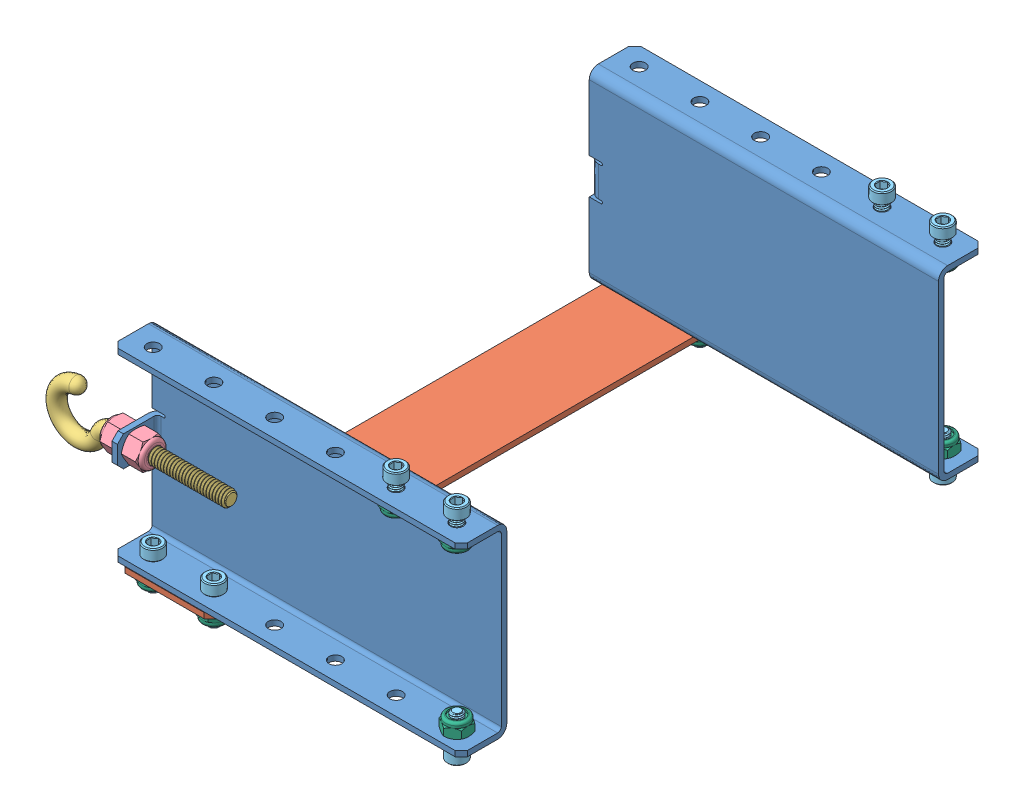
SolidWorks assembly Battery Tray Assembly, configuration Default. Lengths in mm.
Overall size (179.96 96.11 219.07).
26 component instances, 6 part files, 0 mates.
Components (placement in the parent):
- Bracket-1: Bracket [Default] at (142.5014 92.1973 54.8206) size (146.05 77.47 19.05)
- Bracket-2: Bracket [Default] at (142.5014 14.7273 -123.1577) x (1 0 0) z (0 0 -1) size (146.05 77.47 19.05)
- Brace-1: Brace [Default] at (16.1214 12.4413 -34.1685) x (0 0 1) z (-1 0 0) size (219.07 2.29 38.1)
- Hook 0.25-20-1: Hook 0.25-20 [Default] at (36.1824 53.4623 67.5206) x (0 -0.999834 -0.018221) z (0 0.018221 -0.999834) size (25.34 76.35 6.73)
- 0.25-20 Lock Nut-1: 0.25-20 Lock Nut [Default] at (-3.8176 53.4623 67.5206) x (0 -1 0) z (0 0 1) size (11.11 8.13 12.83)
- 0.25-20 Lock Nut-2: 0.25-20 Lock Nut [Default] at (-6.1036 53.4623 67.5206) x (0 1 0) z (0 0 1) size (11.11 8.13 12.83)
- 10-32 x 0.5 in Screw-1: 10-32 x 0.5 in Screw [Default] at (3.4214 4.3133 67.4315) x (1 0 0) z (0 -1 0) size (7.92 7.92 17.75)
- 10-32 Lock Nut-1: 10-32 Lock Nut [Default] at (3.4214 12.4413 67.4315) x (0.837169 0 0.546944) z (0 -1 0) size (9.53 11 5.96)
- 10-32 Lock Nut-2: 10-32 Lock Nut [Default] at (3.4214 12.4413 -135.7685) x (0.837169 0 0.546944) z (0 -1 0) size (9.53 11 5.96)
- 10-32 Lock Nut-3: 10-32 Lock Nut [Default] at (28.8214 12.4413 67.4315) x (0.837169 0 0.546944) z (0 -1 0) size (9.53 11 5.96)
- 10-32 Lock Nut-4: 10-32 Lock Nut [Default] at (28.8214 12.4413 -135.7685) x (0.837169 0 0.546944) z (0 -1 0) size (9.53 11 5.96)
- 10-32 x 0.5 in Screw-2: 10-32 x 0.5 in Screw [Default] at (3.4214 4.3133 -135.7685) x (1 0 0) z (0 -1 0) size (7.92 7.92 17.75)
- 10-32 x 0.5 in Screw-3: 10-32 x 0.5 in Screw [Default] at (28.8214 4.3133 67.4315) x (1 0 0) z (0 -1 0) size (7.92 7.92 17.75)
- 10-32 x 0.5 in Screw-4: 10-32 x 0.5 in Screw [Default] at (28.8214 4.3133 -135.7685) x (1 0 0) z (0 -1 0) size (7.92 7.92 17.75)
- 10-32 x 0.5 in Screw-5: 10-32 x 0.5 in Screw [Default] at (130.4214 24.2523 67.4315) x (-0.837169 0 -0.546944) z (0 1 0) size (7.92 7.92 17.75)
- 10-32 Lock Nut-5: 10-32 Lock Nut [Default] at (130.4214 17.0133 67.4315) x (-1 0 0) z (0 1 0) size (9.53 11 5.96)
- 10-32 x 0.5 in Screw-6: 10-32 x 0.5 in Screw [Default] at (130.4214 24.2523 -135.7685) x (-0.837169 0 -0.546944) z (0 1 0) size (7.92 7.92 17.75)
- 10-32 Lock Nut-6: 10-32 Lock Nut [Default] at (130.4214 17.0133 -135.7685) x (-1 0 0) z (0 1 0) size (9.53 11 5.96)
- 10-32 x 0.5 in Screw-7: 10-32 x 0.5 in Screw [Default] at (130.4214 82.6723 -135.7685) x (1 0 0) z (0 -1 0) size (7.92 7.92 17.75)
- 10-32 x 0.5 in Screw-8: 10-32 x 0.5 in Screw [Default] at (105.0214 82.6723 -135.7685) x (1 0 0) z (0 -1 0) size (7.92 7.92 17.75)
- 10-32 x 0.5 in Screw-9: 10-32 x 0.5 in Screw [Default] at (130.4214 82.6723 67.4315) x (1 0 0) z (0 -1 0) size (7.92 7.92 17.75)
- 10-32 x 0.5 in Screw-10: 10-32 x 0.5 in Screw [Default] at (105.0214 82.6723 67.4315) x (1 0 0) z (0 -1 0) size (7.92 7.92 17.75)
- 10-32 Lock Nut-7: 10-32 Lock Nut [Default] at (130.4214 89.9113 -135.7685) x (0.837169 0 0.546944) z (0 -1 0) size (9.53 11 5.96)
- 10-32 Lock Nut-8: 10-32 Lock Nut [Default] at (105.0214 89.9113 -135.7685) x (0.837169 0 0.546944) z (0 -1 0) size (9.53 11 5.96)
- 10-32 Lock Nut-9: 10-32 Lock Nut [Default] at (130.4214 89.9113 67.4315) x (0.837169 0 0.546944) z (0 -1 0) size (9.53 11 5.96)
- 10-32 Lock Nut-10: 10-32 Lock Nut [Default] at (105.0214 89.9113 67.4315) x (0.837169 0 0.546944) z (0 -1 0) size (9.53 11 5.96)
